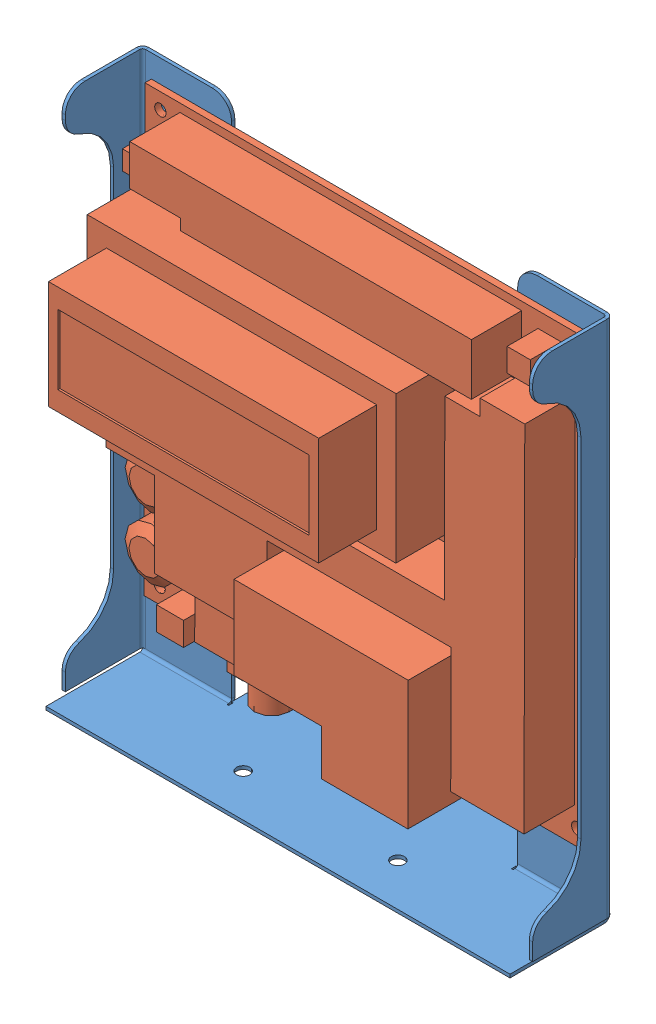
SolidWorks assembly TinahAssembly, configuration Default. Lengths in mm.
Overall size (121.72 135.86 54.15).
2 component instances, 2 part files, 2 mates.
Components (placement in the parent):
- TinahHolder-1: TinahHolder [Default] at (29.8457 21.9877 148.5252) size (121.72 135.86 45)
- Tinah Board-1: Tinah Board [Default] at (29.9689 93.4733 146.0252) x (0.999998 -0.002121 0) z (-0.002121 -0.999998 0) size (116.25 54.15 115)
Mates (geometry in assembly coordinates):
- Concentric8: concentric aligned: circle of TinahHolder-1; circle of Tinah Board-1
- Coincident3: coincident anti-aligned: plane of TinahHolder-1 through (29.8457 21.9877 146.0252) normal (0 0 1); plane of Tinah Board-1 through (87.8468 35.8504 146.0252) normal (0 0 -1)
